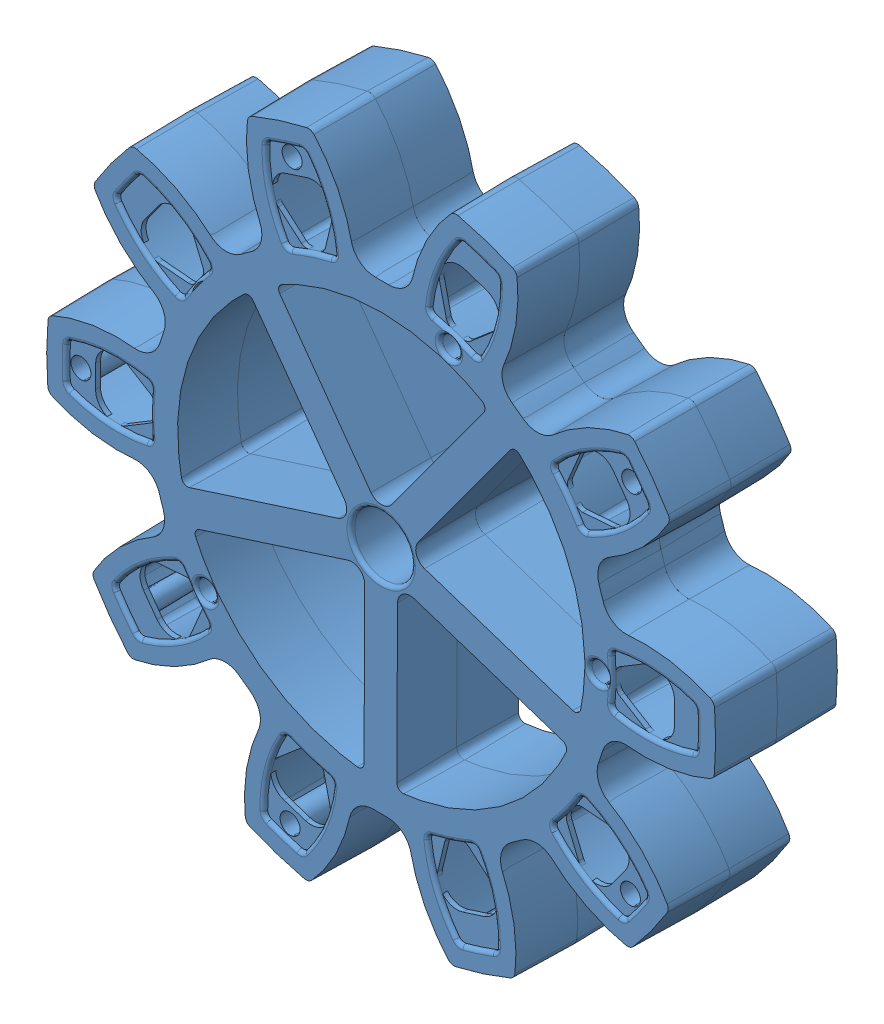
SolidWorks assembly Assem2, configuration Default. Lengths in mm.
Overall size (282.21 276.15 203.16).
2 component instances, 1 part files, 3 mates.
Components (placement in the parent):
- Gear_Half-1: Gear_Half [Default] at origin size (280.29 274.19 200)
- Gear_Half-2: Gear_Half [Default] x (-0.999975 0.007024 0) z (0 0 -1) size (280.29 274.19 200)
Mates (geometry in assembly coordinates):
- Coincident1: coincident: plane of Gear_Half-1 through (0 0 0) normal (0 0 -1); plane of Gear_Half-2 through (0 0 0) normal (0 0 1)
- Concentric1: concentric: circle of Gear_Half-1; circle of Gear_Half-2
- Concentric2: concentric aligned: circle of Gear_Half-1; circle of Gear_Half-2
